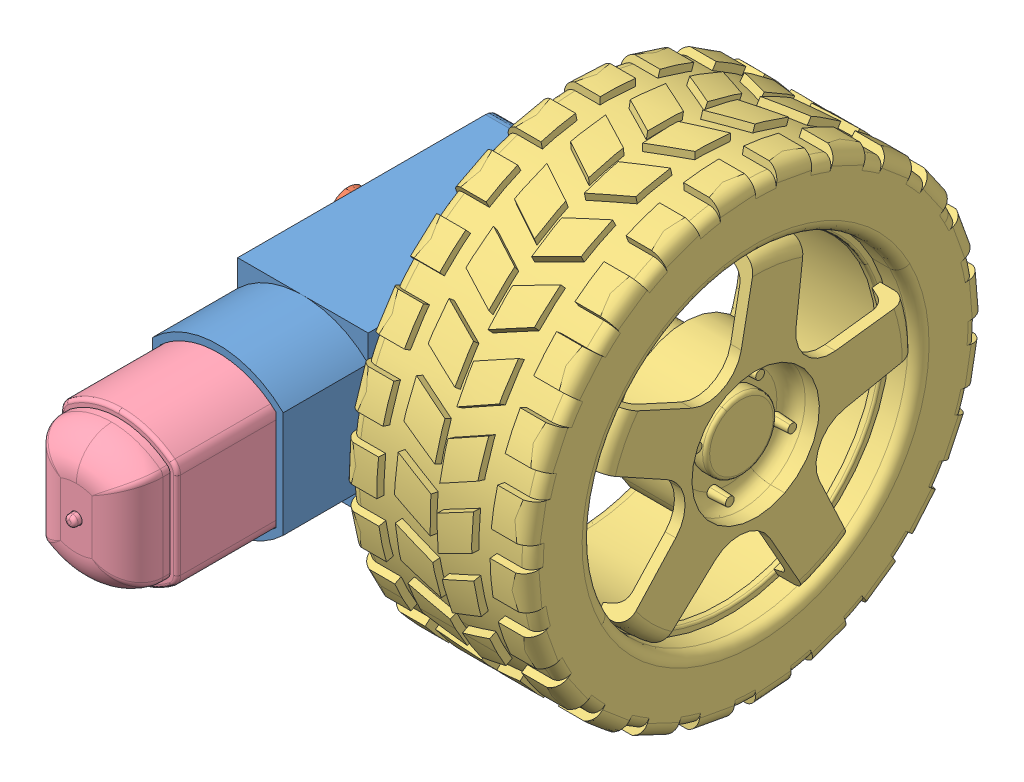
SolidWorks assembly Bo Motor With Wheel, configuration Default. Lengths in mm.
Overall size (57.56 87.54 101.77).
5 component instances, 4 part files, 0 mates.
Components (placement in the parent):
- Real Bo Motor With Wheel.STEP-1: Real Bo Motor With Wheel.STEP [Default] at origin size (57.56 87.54 101.77)
  - Real Bo Motor Gear Box.STEP-1: Real Bo Motor Gear Box.STEP [Default] x (0 0 -1) z (1 0 0) size (54 22.5 18.44)
  - Shaft.STEP-1: Shaft.STEP [Default] at (0 0 -7.5) x (0 0.992156 0.12501) z (1 0 0) size (7.2 7.2 37.26)
  - Real Wheel.STEP-1: Real Wheel.STEP [Default] at (16.952 -28.7718 37.2995) x (1 0 0) z (0 0.457639 -0.889138) size (28.2 65 65)
  - Real Bo Motor Frame.STEP-1: Real Bo Motor Frame.STEP [Default] at (0 0 18.5) x (-1 0 0) z (0 1 0) size (16.44 32 20.5)
